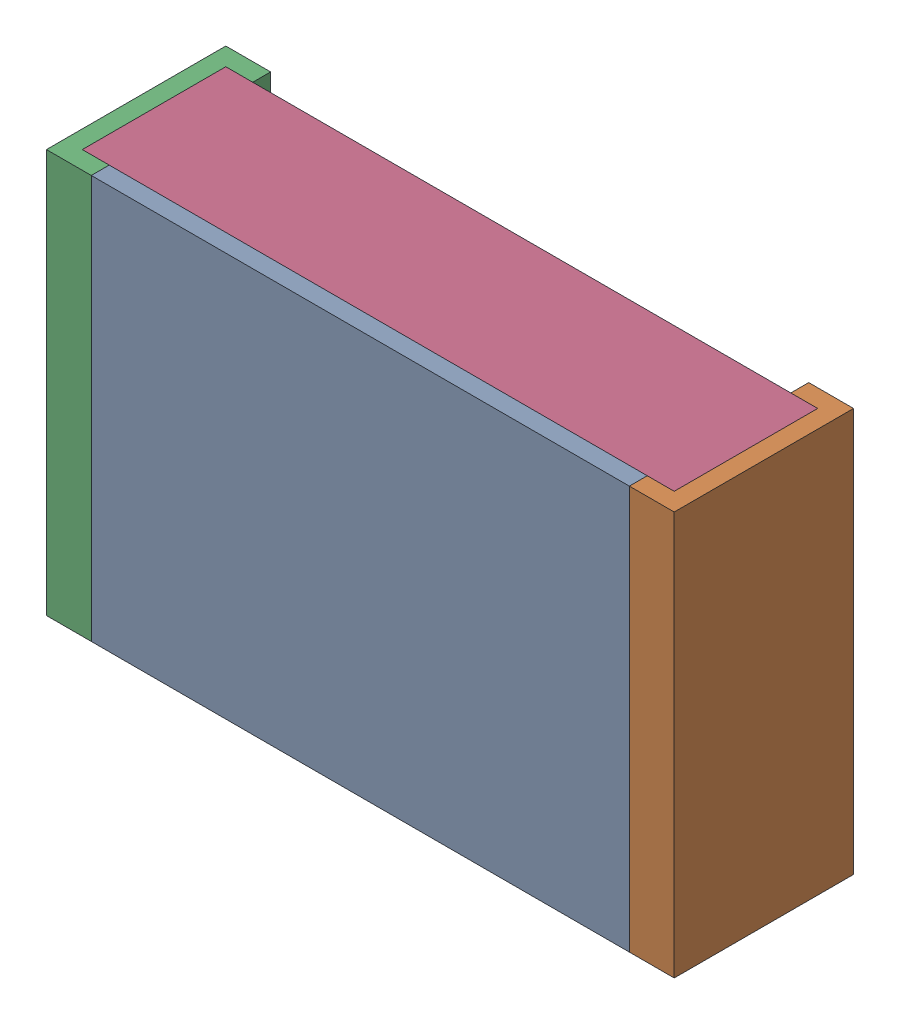
SolidWorks assembly R21, configuration По умолчанию. Lengths in mm.
Overall size (2.1 1.35 0.6).
5 component instances, 3 part files, 0 mates.
Components (placement in the parent):
- RESC2012X06N.step-1-1: RESC2012X06N.step-1 [По умолчанию] at origin size (2.1 1.35 0.6)
  - RESC2012X06N.step-Part-1-1: RESC2012X06N.step-Part-1 [По умолчанию] at (-0.9 -0.675 0.54) size (1.8 1.35 0.06)
  - RESC2012X06N.step-Part-2-1: RESC2012X06N.step-Part-2 [По умолчанию] at (1.05 0.675 0) x (-1 0 0) z (0 0 1) size (0.15 1.35 0.6)
  - RESC2012X06N.step-Part-2-2: RESC2012X06N.step-Part-2 [По умолчанию] at (-1.05 -0.675 0) size (0.15 1.35 0.6)
  - RESC2012X06N.step-Part-3-1: RESC2012X06N.step-Part-3 [По умолчанию] at (-1.05 -0.675 0) size (1.98 1.35 0.48)
